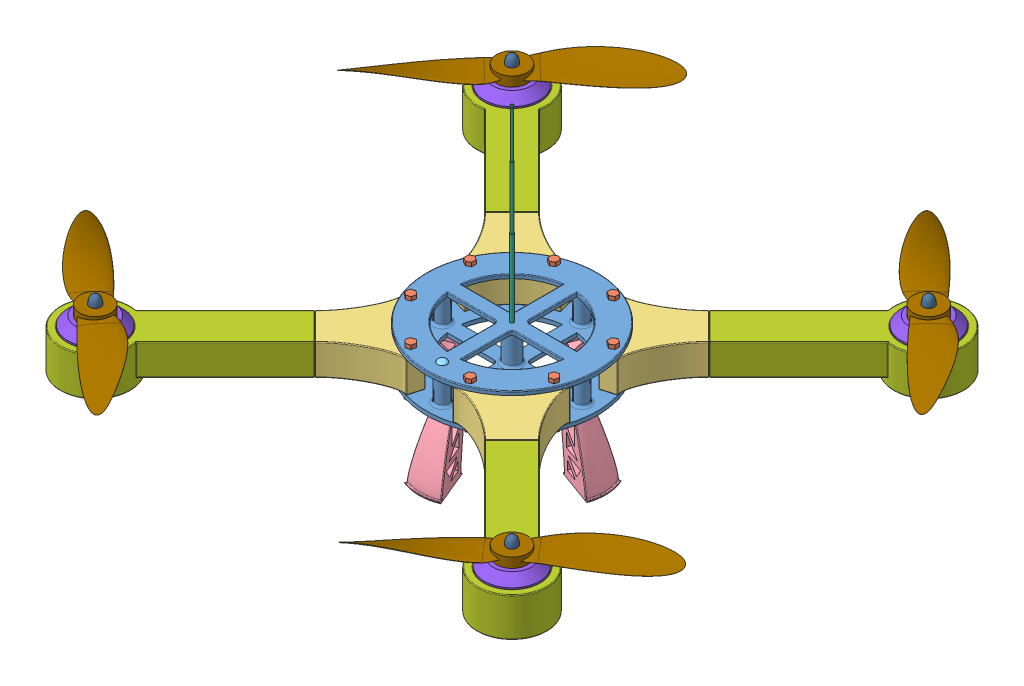
SolidWorks assembly Final_Assembly, configuration Default. Lengths in mm.
Overall size (2192.92 953.82 2186.35).
40 component instances, 10 part files, 20 mates.
Components (placement in the parent):
- Base-Connector-Assembly-1: Base-Connector-Assembly [Default] at (136.1487 59.8889 143.4102) size (752.9 953.82 752.71)
  - Drone_BaseF-1: Drone_BaseF [Default] at (185.4655 243.7928 430.4737) size (558.8 129.54 558.8)
  - Bolt-1: Bolt [Default] at (-49.1999 243.7928 527.6753) x (0.986044 0 0.166487) z (-0.166487 0 0.986044) size (26.4 152.4 30.48)
  - Bolt-2: Bolt [Default] at (88.2639 243.7928 665.1391) x (0.691609 0 -0.722272) z (0.722272 0 0.691609) size (26.4 152.4 30.48)
  - Bolt-3: Bolt [Default] at (-49.1999 243.7928 333.2721) size (26.4 152.4 30.48)
  - Bolt-4: Bolt [Default] at (88.2639 243.7928 195.8083) size (26.4 152.4 30.48)
  - Bolt-5: Bolt [Default] at (282.6671 243.7928 195.8083) size (26.4 152.4 30.48)
  - Bolt-6: Bolt [Default] at (420.1309 243.7928 333.2721) size (26.4 152.4 30.48)
  - Bolt-7: Bolt [Default] at (420.1309 243.7928 527.6753) x (0.258858 0 0.965915) z (-0.965915 0 0.258858) size (26.4 152.4 30.48)
  - Bolt-8: Bolt [Default] at (282.6671 243.7928 665.1391) size (26.4 152.4 30.48)
  - Drone_Connector-2: Drone_Connector [Default] at (185.4655 256.4928 430.4737) size (312.47 116.72 314.78)
  - Drone_Connector-3: Drone_Connector [Default] at (185.4655 256.4928 430.4737) x (0 0 -1) z (1 0 0) size (312.47 116.72 314.78)
  - Drone_Connector-4: Drone_Connector [Default] at (185.4655 358.0928 430.4737) x (0 0 1) z (1 0 0) size (312.47 116.72 314.78)
  - Drone_Connector-5: Drone_Connector [Default] at (185.4655 256.4928 430.4737) x (0 0 1) z (-1 0 0) size (312.47 116.72 314.78)
  - Drone_LandingGear-5: Drone_LandingGear [Default] at (-101.6635 31.936 372.7632) x (0.910912 0 0.4126) z (-0.4126 0 0.910912) size (160.77 212.14 149.82)
  - Drone_LandingGear-6: Drone_LandingGear [Default] at (131.2263 31.936 719.593) x (0.37996 0 -0.925003) z (0.925003 0 0.37996) size (160.77 212.14 149.82)
  - Drone_LandingGear-7: Drone_LandingGear [Default] at (476.7222 31.936 480.6309) x (-0.93978 0 -0.341781) z (0.341781 0 -0.93978) size (160.77 212.14 149.82)
  - Drone_LandingGear-8: Drone_LandingGear [Default] at (239.219 31.936 141.0888) x (-0.375406 0 0.92686) z (-0.92686 0 -0.375406) size (160.77 212.14 149.82)
  - Drone_LEDindicator-1: Drone_LEDindicator [Default] at (187.5441 370.7928 657.6139) x (0.818355 0 -0.574713) z (0.574713 0 0.818355) size (30.48 9.04 30.48)
  - Drone_ReceiverAntenna-2: Drone_ReceiverAntenna [Default] at (185.4655 368.2528 430.4737) x (0.079137 0 -0.996864) z (0.996864 0 0.079137) size (12.7 617.22 12.7)
- Drone_Arm-1: Drone_Arm [Default] at (-405.7865 316.3817 1211.4821) x (0.707107 0 -0.707107) z (0.707107 0 0.707107) size (685.8 127 228.6)
- Drone_Arm-2: Drone_Arm [Default] at (-315.984 316.3817 -153.5168) x (0.707107 0 0.707107) z (-0.707107 0 0.707107) size (685.8 127 228.6)
- Drone_Arm-3: Drone_Arm [Default] at (1049.0149 316.3817 -63.7143) x (-0.707107 0 0.707107) z (-0.707107 0 -0.707107) size (685.8 127 228.6)
- Drone_Arm-4: Drone_Arm [Default] at (959.2124 316.3817 1301.2846) x (-0.707107 0 -0.707107) z (0.707107 0 -0.707107) size (685.8 127 228.6)
- Motor-Prop-Assembly-2: Motor-Prop-Assembly [Default] at (-156.2241 198.5003 1281.1756) x (-0.455422 0 0.890276) z (-0.890276 0 -0.455422) size (374.35 272.73 819.28)
  - Drone_Motor-1: Drone_Motor [Default] at (71.1352 63.9264 193.4958) size (180.88 262.57 180.88)
  - Drone_Propeller-1: Drone_Propeller [Default] at (64.4288 265.9003 216.2726) x (0.947297 0.155574 0.280045) z (-0.282654 -0.005549 0.959206) size (143.47 63.53 809.67)
  - Drone_PropNut-1: Drone_PropNut [Default] at (71.1352 281.9822 193.4958) size (35.36 29.21 35.36)
- Motor-Prop-Assembly-3: Motor-Prop-Assembly [Default] at (-326.6797 198.5003 -311.9154) x (0.868323 0 0.496) z (-0.496 0 0.868323) size (374.35 272.73 819.28)
  - Drone_Motor-1: Drone_Motor [Default] at (71.1352 63.9264 193.4958) size (180.88 262.57 180.88)
  - Drone_Propeller-1: Drone_Propeller [Default] at (64.4288 265.9003 216.2726) x (0.947297 0.155574 0.280045) z (-0.282654 -0.005549 0.959206) size (143.47 63.53 809.67)
  - Drone_PropNut-1: Drone_PropNut [Default] at (71.1352 281.9822 193.4958) size (35.36 29.21 35.36)
- Motor-Prop-Assembly-4: Motor-Prop-Assembly [Default] at (800.8677 198.5003 -143.1397) x (0.49736 0 -0.867544) z (0.867544 0 0.49736) size (374.35 272.73 819.28)
  - Drone_Motor-1: Drone_Motor [Default] at (71.1352 63.9264 193.4958) size (180.88 262.57 180.88)
  - Drone_Propeller-1: Drone_Propeller [Default] at (64.4288 265.9003 216.2726) x (0.947297 0.155574 0.280045) z (-0.282654 -0.005549 0.959206) size (143.47 63.53 809.67)
  - Drone_PropNut-1: Drone_PropNut [Default] at (71.1352 281.9822 193.4958) size (35.36 29.21 35.36)
- Motor-Prop-Assembly-5: Motor-Prop-Assembly [Default] at (950.2347 198.5003 1455.3756) x (-0.815783 0 -0.578358) z (0.578358 0 -0.815783) size (374.35 272.73 819.28)
  - Drone_Motor-1: Drone_Motor [Default] at (71.1352 63.9264 193.4958) size (180.88 262.57 180.88)
  - Drone_Propeller-1: Drone_Propeller [Default] at (64.4288 265.9003 216.2726) x (0.947297 0.155574 0.280045) z (-0.282654 -0.005549 0.959206) size (143.47 63.53 809.67)
  - Drone_PropNut-1: Drone_PropNut [Default] at (71.1352 281.9822 193.4958) size (35.36 29.21 35.36)
Mates (geometry in assembly coordinates):
- Coincident2: coincident anti-aligned: plane of Base-Connector-Assembly-1/Drone_Connector-2 through (43.2263 316.3817 852.2718) normal (-0.707107 0 0.707107); plane of Drone_Arm-1 through (-1.675 316.3817 807.3706) normal (0.707107 0 -0.707107)
- Coincident3: coincident anti-aligned: plane of Base-Connector-Assembly-1/Drone_Connector-2 through (7.3052 405.2817 816.3508) normal (0.707107 0 0.707107); plane of Drone_Arm-1 through (7.3052 405.2817 816.3508) normal (-0.707107 0 -0.707107)
- Coincident4: coincident anti-aligned: plane of Base-Connector-Assembly-1/Drone_Connector-2 through (7.3052 405.2817 816.3508) normal (0 -1 0); plane of Drone_Arm-1 through (7.3052 405.2817 816.3508) normal (0 1 0)
- Coincident5: coincident anti-aligned: plane of Base-Connector-Assembly-1/Drone_Connector-5 through (43.2263 316.3817 295.496) normal (-0.707107 0 -0.707107); plane of Drone_Arm-2 through (88.1275 316.3817 250.5947) normal (0.707107 0 0.707107)
- Coincident6: coincident anti-aligned: plane of Base-Connector-Assembly-1/Drone_Connector-5 through (79.1473 405.2817 259.5749) normal (0 -1 0); plane of Drone_Arm-2 through (79.1473 405.2817 259.5749) normal (0 1 0)
- Coincident7: coincident anti-aligned: plane of Base-Connector-Assembly-1/Drone_Connector-5 through (79.1473 405.2817 259.5749) normal (-0.707107 0 0.707107); plane of Drone_Arm-2 through (79.1473 405.2817 259.5749) normal (0.707107 0 -0.707107)
- Coincident10: coincident anti-aligned: plane of Base-Connector-Assembly-1/Drone_Connector-3 through (600.0021 316.3817 852.2718) normal (0.707107 0 0.707107); plane of Drone_Arm-4 through (555.1009 316.3817 897.1731) normal (-0.707107 0 -0.707107)
- Coincident11: coincident anti-aligned: plane of Base-Connector-Assembly-1/Drone_Connector-3 through (564.0811 405.2817 888.1929) normal (0 -1 0); plane of Drone_Arm-4 through (564.0811 405.2817 888.1929) normal (0 1 0)
- Coincident12: coincident anti-aligned: plane of Base-Connector-Assembly-1/Drone_Connector-3 through (564.0811 405.2817 888.1929) normal (0.707107 0 -0.707107); plane of Drone_Arm-4 through (564.0811 405.2817 888.1929) normal (-0.707107 0 0.707107)
- Coincident14: coincident anti-aligned: plane of Base-Connector-Assembly-1/Drone_Connector-4 through (600.0021 417.9817 295.496) normal (0.707107 0 -0.707107); plane of Drone_Arm-3 through (644.9034 316.3817 340.3972) normal (-0.707107 0 0.707107)
- Coincident15: coincident anti-aligned: plane of Base-Connector-Assembly-1/Drone_Connector-4 through (635.9232 379.8817 331.417) normal (-0.707107 0 -0.707107); plane of Drone_Arm-3 through (635.9232 405.2817 331.417) normal (0.707107 0 0.707107)
- Coincident16: coincident anti-aligned: plane of Base-Connector-Assembly-1/Drone_Connector-4 through (617.9627 405.2817 313.4565) normal (0 -1 0); plane of Drone_Arm-3 through (635.9232 405.2817 331.417) normal (0 1 0)
- Width2: width aligned: plane of Motor-Prop-Assembly-2/Drone_Motor-1 through (-363.7772 260.231 1262.0366) normal (0 -1 0); plane of Motor-Prop-Assembly-2/Drone_Motor-1 through (-389.8045 448.7325 1312.9159) normal (0 1 0); plane of Drone_Arm-1 through (-360.8853 290.9817 1256.3834) normal (0 -1 0); plane of Drone_Arm-1 through (-315.984 417.9817 1301.2846) normal (0 1 0)
- Width3: width aligned: plane of Motor-Prop-Assembly-5/Drone_Motor-1 through (998.9334 260.231 1252.7108) normal (0 -1 0); plane of Motor-Prop-Assembly-5/Drone_Motor-1 through (952.3114 448.7325 1219.6577) normal (0 1 0); plane of Drone_Arm-4 through (1004.1137 290.9817 1256.3834) normal (0 -1 0); plane of Drone_Arm-4 through (1049.0149 417.9817 1211.4821) normal (0 1 0)
- Width4: width aligned: plane of Motor-Prop-Assembly-4/Drone_Motor-1 through (1035.696 448.7325 -163.7046) normal (0 1 0); plane of Motor-Prop-Assembly-4/Drone_Motor-1 through (1007.2719 260.231 -114.1245) normal (0 -1 0); plane of Drone_Arm-3 through (959.2124 417.9817 -153.5168) normal (0 1 0); plane of Drone_Arm-3 through (1004.1137 290.9817 -108.6156) normal (0 -1 0)
- Width5: width aligned: plane of Motor-Prop-Assembly-3/Drone_Motor-1 through (-355.3714 260.231 -105.466) normal (0 -1 0); plane of Motor-Prop-Assembly-3/Drone_Motor-1 through (-305.7468 448.7325 -77.1196) normal (0 1 0); plane of Drone_Arm-2 through (-360.8853 290.9817 -108.6156) normal (0 -1 0); plane of Drone_Arm-2 through (-405.7865 417.9817 -63.7143) normal (0 1 0)
- Concentric1: concentric aligned: circle of Drone_Arm-4; cylinder of Motor-Prop-Assembly-5/Drone_Motor-1 through (1004.1137 499.5325 1256.3834) axis (0 -1 0) radius 90.4408
- Concentric2: concentric aligned: circle of Drone_Arm-1; cylinder of Motor-Prop-Assembly-2/Drone_Motor-1 through (-360.8853 499.5325 1256.3834) axis (0 -1 0) radius 90.4408
- Concentric3: concentric aligned: circle of Drone_Arm-3; cylinder of Motor-Prop-Assembly-4/Drone_Motor-1 through (1004.1137 499.5325 -108.6156) axis (0 -1 0) radius 90.4408
- Concentric4: concentric aligned: circle of Drone_Arm-2; cylinder of Motor-Prop-Assembly-3/Drone_Motor-1 through (-360.8853 499.5325 -108.6156) axis (0 -1 0) radius 90.4408
